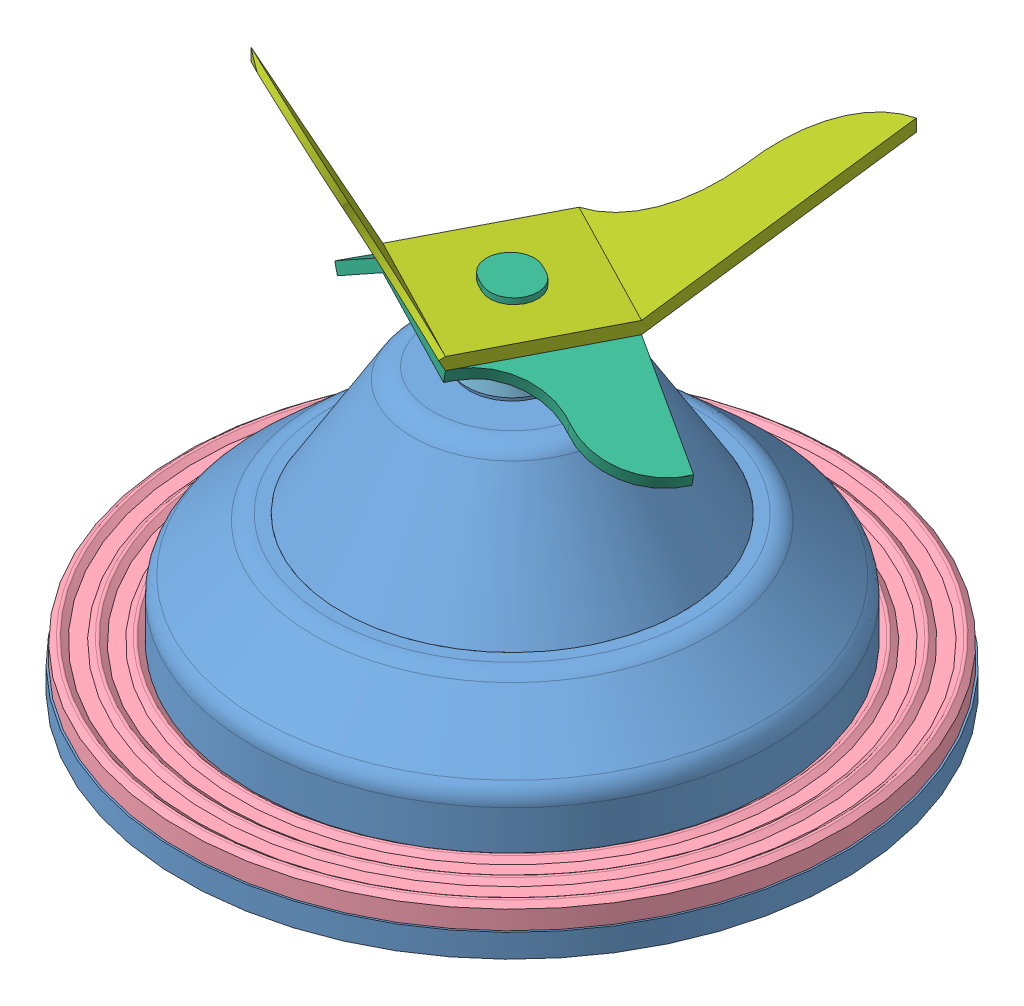
SolidWorks assembly Blade-subassem, configuration Default. Lengths in mm.
Overall size (69.04 63.84 69.04).
7 component instances, 7 part files, 16 mates.
Components (placement in the parent):
- Blade-C-1: Blade-C [Default] at (10.9016 32.864 62.9869) size (69.04 29.87 69.04)
- Blade-B-1: Blade-B [Default] at (10.9016 38.9473 62.9869) size (9.82 0.84 9.82)
- Blade-A-1: Blade-A [Default] at (10.9016 39.7855 62.9869) x (-0.095157 0 0.995462) z (0.995462 0 0.095157) size (39.73 13.71 39.75)
- Blade-D-1: Blade-D [Default] at (10.9016 35.3024 62.9869) size (68.64 2.84 68.64)
- Blade-E-1: Blade-E [Default] at (10.9016 62.7344 62.9869) size (9.53 3.67 9.53)
- Blade-F-1: Blade-F [Default] at (10.9016 40.2173 62.9869) x (0.888483 0 0.458909) z (-0.458909 0 0.888483) size (39.67 36.96 15.36)
- Blade-G-2: Blade-G [Default] at (10.9016 68.5891 62.9869) x (-0.888483 0 -0.458909) z (0.458909 0 -0.888483) size (15.24 21.32 46.85)
Mates (geometry in assembly coordinates):
- Concentric1: concentric aligned: circle of Blade-C-1; cylinder of Blade-D-1 through (10.9016 35.3024 62.9869) axis (0 -1 0) radius 34.3218
- Coincident3: coincident anti-aligned: plane of Blade-C-1 through (10.9016 35.3024 62.9869) normal (0 1 0); circle of Blade-D-1
- Concentric2: concentric aligned: circle of Blade-C-1; cylinder of Blade-D-1 through (10.9016 35.3024 62.9869) axis (0 -1 0) radius 34.3218
- Concentric3: concentric anti-aligned: circle of Blade-C-1; circle of Blade-B-1
- Coincident4: coincident anti-aligned: plane of Blade-C-1 through (10.9016 39.7855 62.9869) normal (0 -1 0); plane of Blade-B-1 through (10.9016 39.7855 62.9869) normal (0 1 0)
- Concentric5: concentric anti-aligned: cylinder of Blade-C-1 through (10.9016 32.864 62.9869) axis (0 -1 0) radius 2.9337; cylinder of Blade-F-1 through (10.9016 33.5371 62.9869) axis (0 1 0) radius 2.9337
- Concentric6: concentric aligned: circle of Blade-C-1; circle of Blade-E-1
- Coincident7: coincident anti-aligned: plane of Blade-C-1 through (10.9016 62.7344 62.9869) normal (0 1 0); plane of Blade-E-1 through (10.9016 62.7344 62.9869) normal (0 -1 0)
- Coincident8: coincident anti-aligned: plane of Blade-E-1 through (10.9016 66.4047 62.9869) normal (0 1 0); plane of Blade-F-1 through (10.9016 66.4047 62.9869) normal (0 -1 0)
- Parallel1: parallel aligned: plane of Blade-C-1 through (11.1162 41.2714 62.5714) normal (0.458909 0 -0.888483); plane of Blade-F-1 through (7.6282 68.5891 52.7197) normal (0.458909 0 -0.888483)
- Coincident15: coincident anti-aligned: plane of Blade-F-1 through (10.9016 68.5891 62.9869) normal (0 1 0); plane of Blade-G-2 through (10.9016 68.5891 62.9869) normal (0 -1 0)
- Concentric9: concentric aligned: cylinder of Blade-F-1 through (11.292 70.4941 63.1885) axis (0 -1 0) radius 2.5146; cylinder of Blade-G-2 through (11.292 69.8845 63.1885) axis (0 -1 0) radius 2.5146
- Concentric12: concentric aligned: cylinder of Blade-F-1 through (10.5111 70.4941 62.7852) axis (0 -1 0) radius 2.5146; cylinder of Blade-G-2 through (10.5111 69.8845 62.7852) axis (0 -1 0) radius 2.5146
- Concentric15: concentric aligned: circle of Blade-A-1; circle of Blade-F-1
- Coincident19: coincident anti-aligned: plane of Blade-B-1 through (10.9016 38.9473 62.9869) normal (0 -1 0); plane of Blade-A-1 through (10.9016 38.9473 62.9869) normal (0 1 0)
- Concentric16: concentric anti-aligned: circle of Blade-C-1; circle of Blade-F-1
